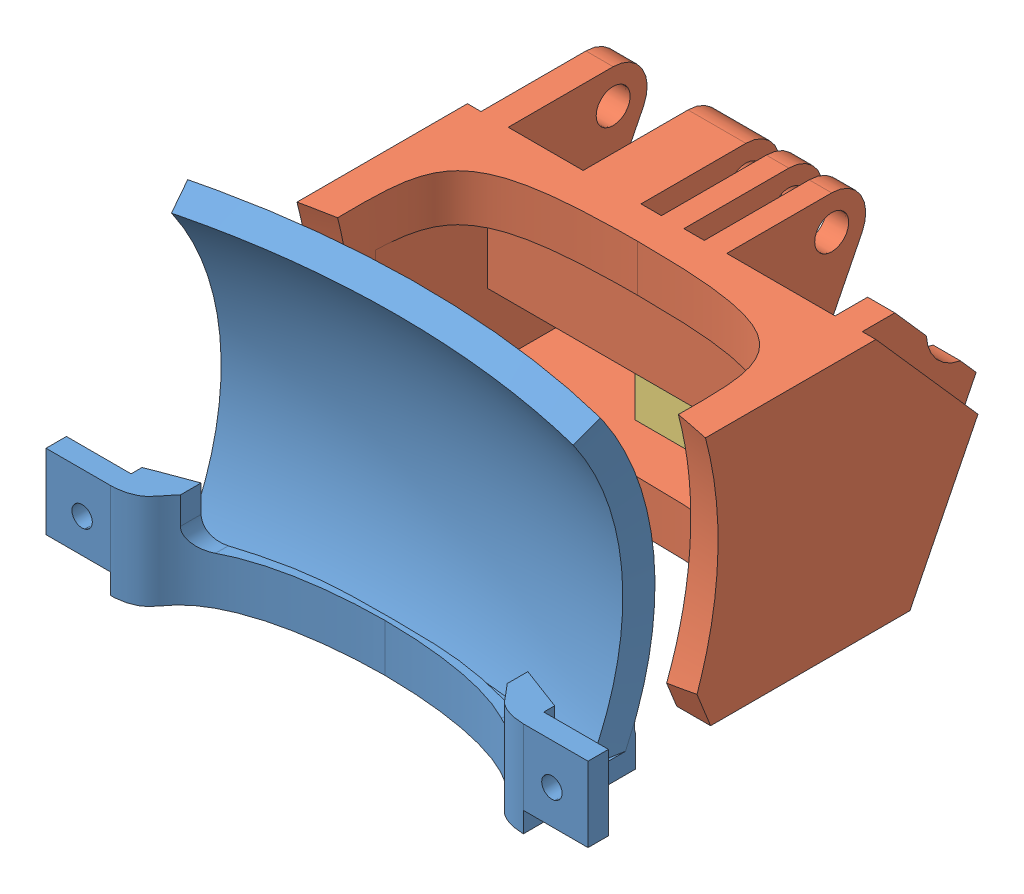
SolidWorks assembly kiss_mount_assembly, configuration Default. Lengths in mm.
Overall size (79.62 49.19 72.52).
3 component instances, 3 part files, 4 mates.
Components (placement in the parent):
- kiss_mount_base-1: kiss_mount_base [Default] at (6.4993 41.9437 113.4577) size (79.62 49.19 35.82)
- kiss_mount_gopro_4-1: kiss_mount_gopro_4 [Default] at (6.8075 19.9437 51.797) size (60 37 49.55)
- kiss_mount_insert-1: kiss_mount_insert [Default] at (-0.6925 33.8169 32.9904) size (15 19 10)
Mates (geometry in assembly coordinates):
- Coincident1: coincident aligned: plane of kiss_mount_base-1 through (-12.4431 19.9437 68.2226) normal (0 -1 0); plane of kiss_mount_gopro_4-1 through (-15.8849 19.9437 47.0272) normal (0 -1 0)
- Coincident2: coincident aligned: plane of kiss_mount_base-1 through (36.8075 19.9437 74.0057) normal (1 0 0); plane of kiss_mount_gopro_4-1 through (36.8075 56.9437 65.2235) normal (1 0 0)
- Coincident3: coincident anti-aligned: plane of kiss_mount_gopro_4-1 through (14.3075 26.9437 31.797) normal (-1 0 0); plane of kiss_mount_insert-1 through (14.3075 22.9437 28.1383) normal (1 0 0)
- Coincident4: coincident aligned: plane of kiss_mount_gopro_4-1 through (-15.8849 19.9437 47.0272) normal (0 -1 0); plane of kiss_mount_insert-1 through (14.3075 19.9437 32.1383) normal (0 -1 0)
